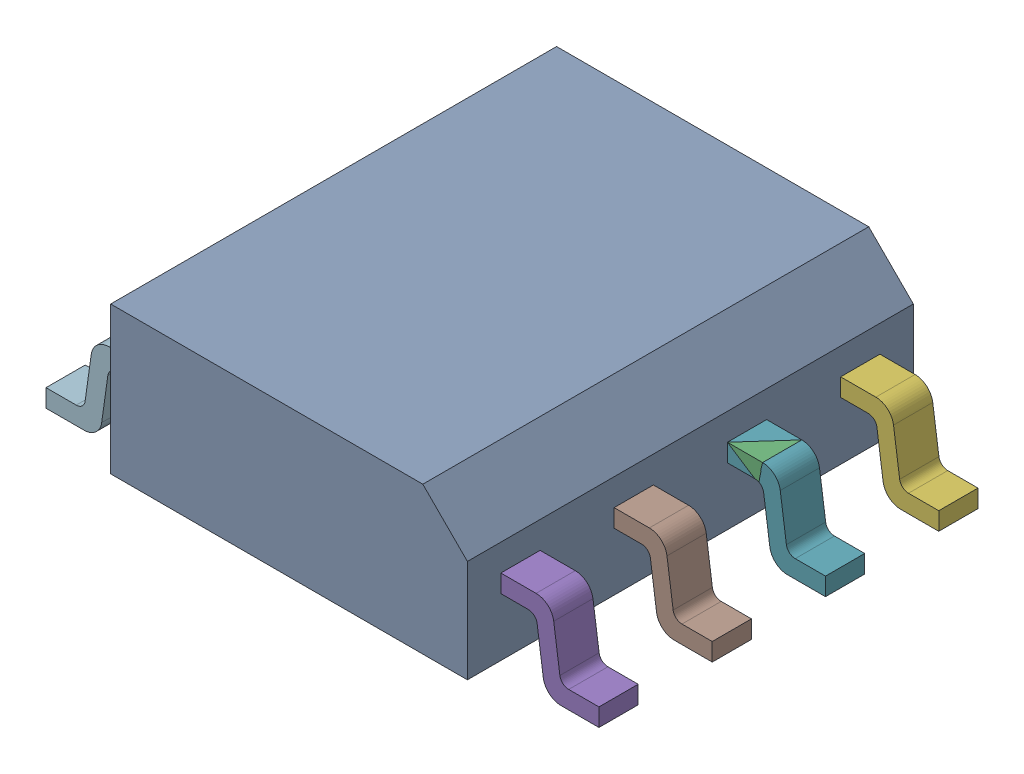
SolidWorks assembly User_Library-HSOP8, configuration По умолчанию. Lengths in mm.
Overall size (6.2 1.75 5).
15 component instances, 2 part files, 0 mates.
Components (placement in the parent):
- User_Library-HSOP8_part_hsop8_____________-1: User_Library-HSOP8_part_hsop8_____________ [По умолчанию] at origin size (4 1.75 5)
- User_Library-HSOP8_Assy_fuss_hsop8_____________-1: User_Library-HSOP8_Assy_fuss_hsop8_____________ [По умолчанию] at (2 0 0) size (1.1 0.95 4.25)
  - User_Library-HSOP8_Fuss_hsop8_____________-1: User_Library-HSOP8_Fuss_hsop8_____________ [По умолчанию] at (0 0 -0.635) size (1.1 0.95 0.44)
  - User_Library-HSOP8_Fuss_hsop8_____________-2: User_Library-HSOP8_Fuss_hsop8_____________ [По умолчанию] at (0 0 0.635) size (1.1 0.95 0.44)
  - User_Library-HSOP8_Fuss_hsop8_____________-3: User_Library-HSOP8_Fuss_hsop8_____________ [По умолчанию] at (0 0 1.905) size (1.1 0.95 0.44)
  - User_Library-HSOP8_Fuss_hsop8_____________-4: User_Library-HSOP8_Fuss_hsop8_____________ [По умолчанию] at (0 0 -1.905) size (1.1 0.95 0.44)
  - User_Library-HSOP8_Fuss_hsop8_____________-5: User_Library-HSOP8_Fuss_hsop8_____________ [По умолчанию] at (0 0 -0.635) size (1.1 0.95 0.44)
  - User_Library-HSOP8_Fuss_hsop8_____________-6: User_Library-HSOP8_Fuss_hsop8_____________ [По умолчанию] at (0 0 0.635) size (1.1 0.95 0.44)
- User_Library-HSOP8_Assy_fuss_hsop8_____________-2: User_Library-HSOP8_Assy_fuss_hsop8_____________ [По умолчанию] at (-2 0 0) x (-1 0 0) z (0 0 -1) size (1.1 0.95 4.25)
  - User_Library-HSOP8_Fuss_hsop8_____________-1: User_Library-HSOP8_Fuss_hsop8_____________ [По умолчанию] at (0 0 -0.635) size (1.1 0.95 0.44)
  - User_Library-HSOP8_Fuss_hsop8_____________-2: User_Library-HSOP8_Fuss_hsop8_____________ [По умолчанию] at (0 0 0.635) size (1.1 0.95 0.44)
  - User_Library-HSOP8_Fuss_hsop8_____________-3: User_Library-HSOP8_Fuss_hsop8_____________ [По умолчанию] at (0 0 1.905) size (1.1 0.95 0.44)
  - User_Library-HSOP8_Fuss_hsop8_____________-4: User_Library-HSOP8_Fuss_hsop8_____________ [По умолчанию] at (0 0 -1.905) size (1.1 0.95 0.44)
  - User_Library-HSOP8_Fuss_hsop8_____________-5: User_Library-HSOP8_Fuss_hsop8_____________ [По умолчанию] at (0 0 -0.635) size (1.1 0.95 0.44)
  - User_Library-HSOP8_Fuss_hsop8_____________-6: User_Library-HSOP8_Fuss_hsop8_____________ [По умолчанию] at (0 0 0.635) size (1.1 0.95 0.44)
